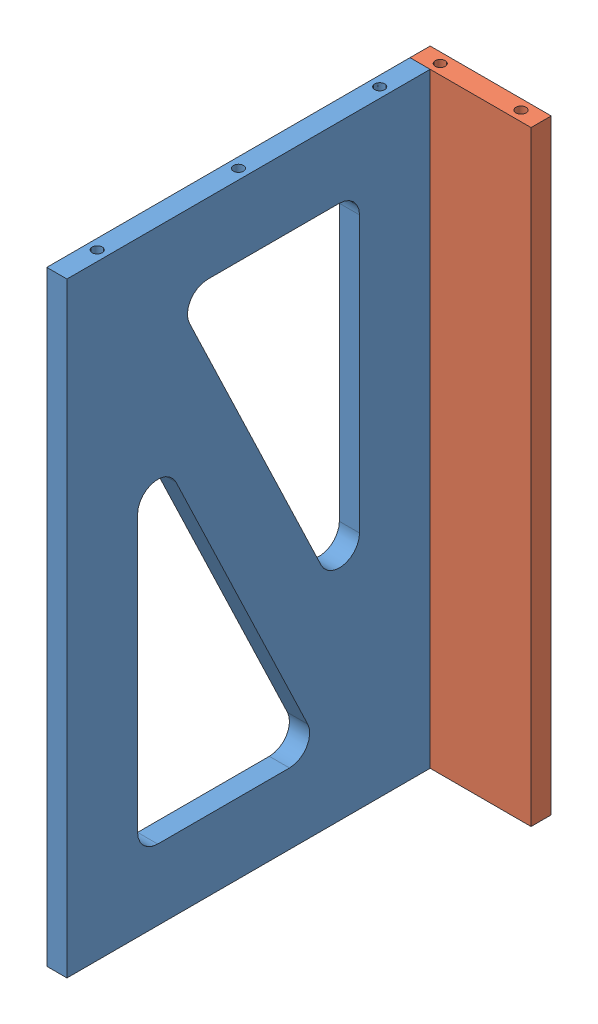
SolidWorks assembly L1, configuration Default. Lengths in mm.
Overall size (60 300 190).
2 component instances, 2 part files, 14 mates.
Components (placement in the parent):
- PLACA L2-1: PLACA L2 [Default] at (0 286.0775 10) x (0 0 1) z (0 1 0) size (180 10 300)
- PLACA L1de-1: PLACA L1de [Default] at (0 -13.9225 0) size (60 300 10)
Mates (geometry in assembly coordinates):
- Coincident1: coincident anti-aligned: plane of ? through (0 0 10) normal (0 0 1); plane of PLACA L2-1 through (10 300 10) normal (0 0 -1)
- Coincident6: coincident aligned: plane of ? through (0 0 10) normal (-1 0 0); plane of PLACA L2-1 through (0 300 10) normal (-1 0 0)
- Coincident7: coincident aligned: plane of ? through (0 300 10) normal (0 1 0); plane of PLACA L2-1 through (10 300 10) normal (0 1 0)
- Concentric1: concentric anti-aligned: cylinder of ? through (5 255 0) axis (0 0 1) radius 3.3; cylinder of ? through (5 255 -37.75) axis (0 0 -1) radius 5
- Coincident8: coincident anti-aligned: plane of ? through (0 0 0) normal (0 0 -1); plane of ? through (5 260 0) normal (0 0 1)
- Concentric2: concentric anti-aligned: cylinder of ? through (5 185 0) axis (0 0 1) radius 3.3; cylinder of ? through (5 185 -37.75) axis (0 0 -1) radius 5
- Coincident9: coincident anti-aligned: plane of ? through (0 0 0) normal (0 0 -1); plane of ? through (0.0609 184.2222 0) normal (0 0 1)
- Concentric3: concentric anti-aligned: cylinder of ? through (5 45 0) axis (0 0 1) radius 3.3; cylinder of ? through (5 45 -37.75) axis (0 0 -1) radius 5
- Coincident10: coincident anti-aligned: plane of ? through (0 0 0) normal (0 0 -1); plane of ? through (5 50 0) normal (0 0 1)
- Concentric4: concentric anti-aligned: cylinder of ? through (5 115 0) axis (0 0 1) radius 3.5551; cylinder of ? through (5 115 -37.75) axis (0 0 -1) radius 3
- Coincident11: coincident anti-aligned: plane of ? through (0 0 0) normal (0 0 -1); plane of ? through (5 120 0) normal (0 0 1)
- Coincident12: coincident aligned: plane of PLACA L2-1 through (10 286.0775 10) normal (0 1 0); plane of PLACA L1de-1 through (0 286.0775 10) normal (0 1 0)
- Coincident13: coincident aligned: plane of PLACA L2-1 through (0 286.0775 10) normal (-1 0 0); plane of PLACA L1de-1 through (0 -13.9225 10) normal (-1 0 0)
- Coincident14: coincident anti-aligned: plane of PLACA L2-1 through (10 286.0775 10) normal (0 0 -1); plane of PLACA L1de-1 through (0 -13.9225 10) normal (0 0 1)
